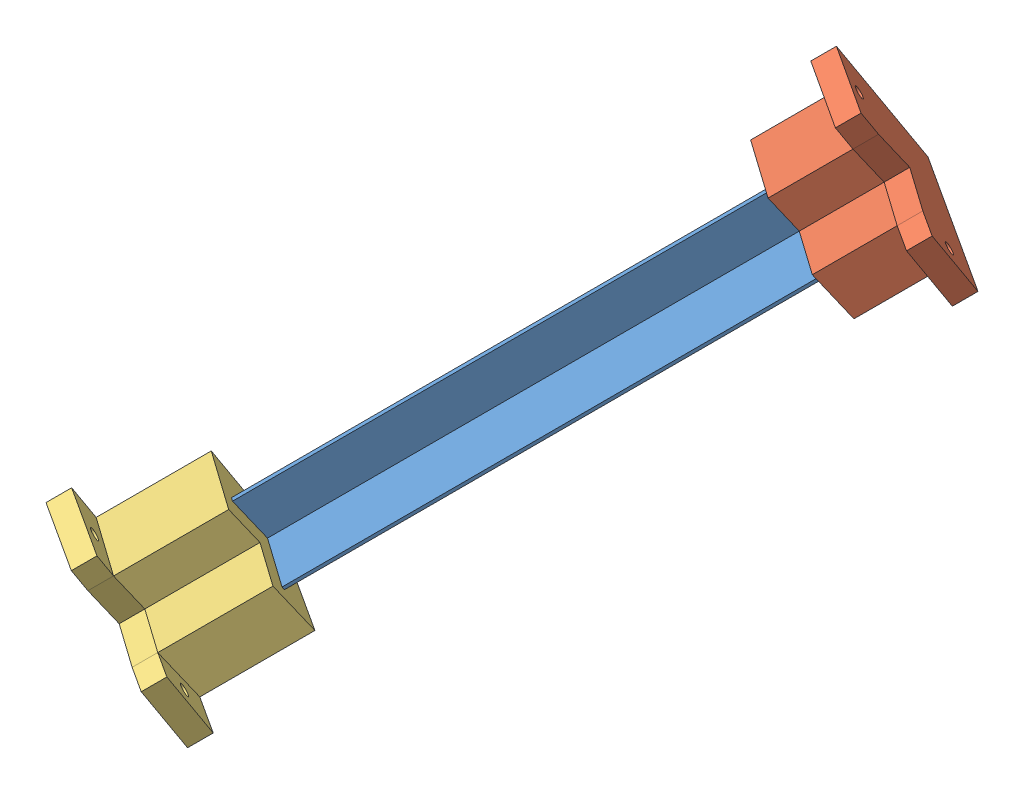
SolidWorks assembly zav-pyramide-arm, configuration По умолчанию. Lengths in mm.
Overall size (46.34 46.34 247.33).
3 component instances, 3 part files, 1 mates.
Components (placement in the parent):
- ZAV-pyramide-profile-1: ZAV-pyramide-profile [По умолчанию] at (90.8026 112.7523 27.8561) size (15 15 200)
- ZAV-pyramide-profile-support-bottom-1: ZAV-pyramide-profile-support-bottom [По умолчанию] at (84.4729 106.4226 62.7443) x (-0.000018 0.999982 0.006018) z (0.006018 0.006018 -0.999964) size (42.97 42.97 54.28)
- ZAV-pyramide-profile-support-top-1: ZAV-pyramide-profile-support-top [По умолчанию] at (84.5526 106.5023 247.8561) x (0 1 0) z (0 0 -1) size (43 43 67.87)
Mates (geometry in assembly coordinates):
- Параллельность5: parallel anti-aligned: plane of ZAV-pyramide-profile-support-bottom-1; plane of ZAV-pyramide-profile-support-top-1
